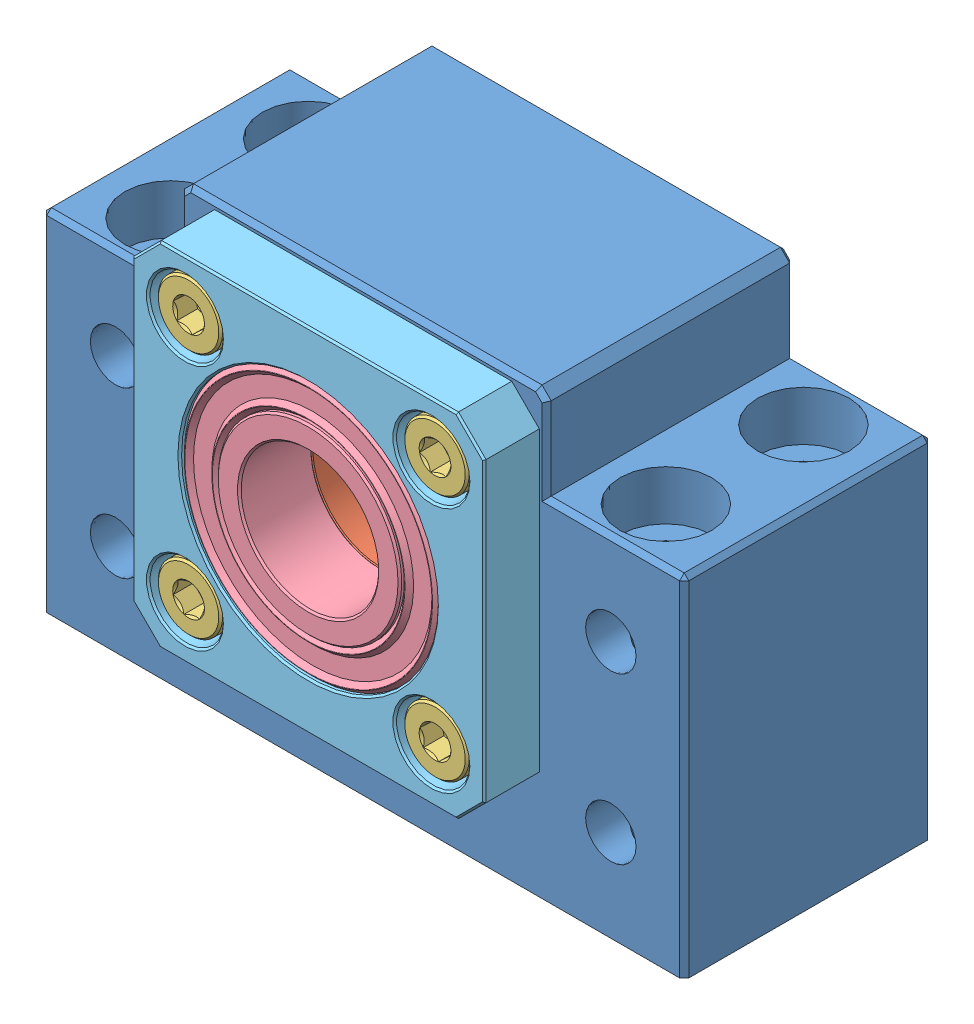
SolidWorks assembly BK-15, configuration 預設. Lengths in mm.
Overall size (70 48 33).
10 component instances, 5 part files, 13 mates.
Components (placement in the parent):
- BK-15-1: BK-15 [預設] at (-94.8687 0 10.5) size (70 48 27)
- 7002-1: 7002 [2385K42] at (-59.8687 28 5) x (0.990923 0.134431 0) z (0 0 1) size (32 32 9)
- 7002-2: 7002 [2385K42] at (-59.8687 28 -4) x (0.987148 0.159806 0) z (0 0 1) size (32 32 9)
- M4x14-1: M4x14 [91290A150] at (-73.3037 41.435 -1.9) x (-0.295694 -0.955283 0) z (0 0 -1) size (7 7 18.34)
- BK-15墊圈-1: BK-15墊圈 [預設] at (-59.8687 28 -16.5) x (-0.003042 -0.999995 0) z (0 0 -1) size (28 28 8)
- BK-15前蓋板-1: BK-15前蓋板 [預設] at (-59.8687 28 10.5) size (38.4 38.4 6)
- M4x14-5: M4x14 [91290A150] at (-46.4337 41.435 -1.9) x (-0.955283 0.295694 0) z (0 0 -1) size (7 7 18.34)
- M4x14-6: M4x14 [91290A150] at (-46.4337 14.565 -1.9) x (0.295694 0.955283 0) z (0 0 -1) size (7 7 18.34)
- M4x14-7: M4x14 [91290A150] at (-73.3037 14.565 -1.9) x (0.955283 -0.295694 0) z (0 0 -1) size (7 7 18.34)
- BK-15墊圈-2: BK-15墊圈 [預設] at (-59.8687 28 16.5) x (0.003042 -0.999995 0) z (0 0 1) size (28 28 8)
Mates (geometry in assembly coordinates):
- 同軸心2: concentric anti-aligned: circle of 7002-2; circle of BK-15墊圈-1
- 重合/共線/共點2: coincident anti-aligned: plane of 7002-2 through (-61.1391 35.8478 -8.5) normal (0 0 -1); plane of BK-15墊圈-1 through (-59.8687 28 -8.5) normal (0 0 1)
- 同軸心3: concentric aligned: circle of 7002-1; circle of 7002-2
- 重合/共線/共點3: coincident anti-aligned: plane of 7002-1 through (-60.9374 35.8778 0.5) normal (0 0 -1); plane of 7002-2 through (-61.4063 37.4981 0.5) normal (0 0 1)
- 同軸心5: concentric anti-aligned: circle of M4x14-1; circle of BK-15前蓋板-1
- 重合/共線/共點4: coincident anti-aligned: plane of M4x14-1 through (-73.3037 41.435 12.1) normal (0 0 -1); plane of BK-15前蓋板-1 through (-71.0537 41.435 12.1) normal (0 0 1)
- 重合/共線/共點5: coincident aligned: plane of BK-15前蓋板-1 through (-59.8687 28 16.5) normal (0 0 1); plane of BK-15墊圈-2 through (-59.8687 3.6221 16.5) normal (0 0 1)
- 同軸心6: concentric anti-aligned: circle of BK-15-1; circle of BK-15前蓋板-1
- 重合/共線/共點6: coincident anti-aligned: plane of BK-15-1 through (-94.8687 0 10.5) normal (0 0 1); plane of BK-15前蓋板-1 through (-59.8687 28 10.5) normal (0 0 -1)
- 同軸心7: concentric anti-aligned: circle of BK-15-1; circle of BK-15前蓋板-1
- 重合/共線/共點7: coincident anti-aligned: plane of BK-15-1 through (-94.8687 0 -16.5) normal (0 -1 0)
- 同軸心8: concentric anti-aligned: circle of BK-15-1; circle of BK-15墊圈-1
- 同軸心9: concentric anti-aligned: circle of BK-15前蓋板-1; circle of BK-15墊圈-2
